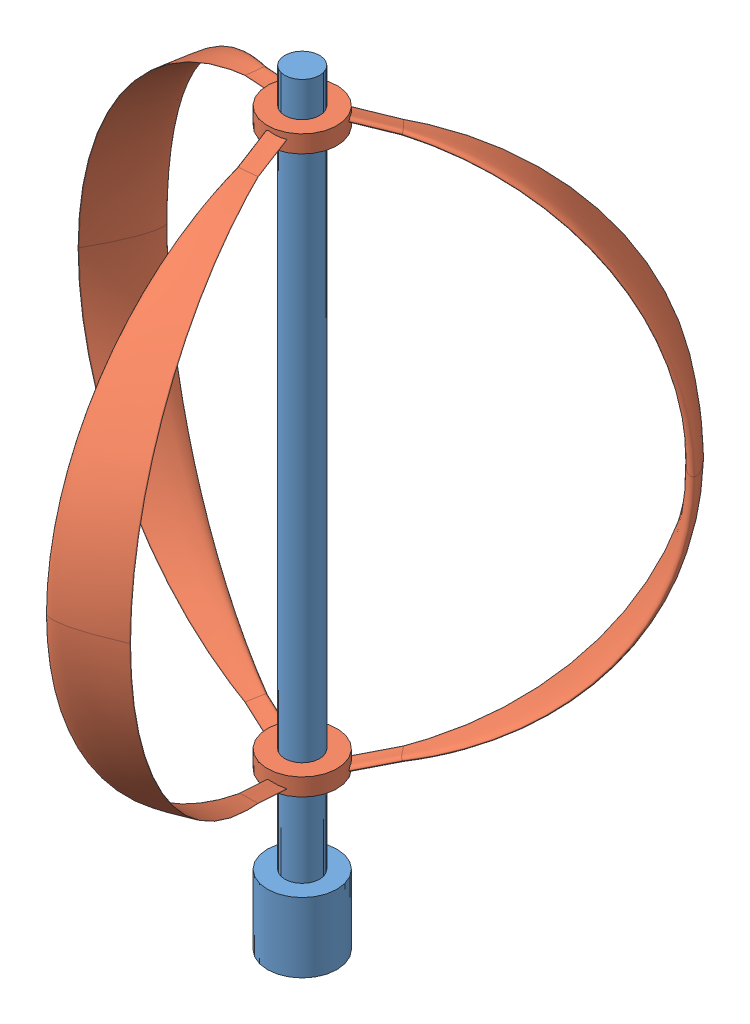
SolidWorks assembly VAWT 3-blade 3D, configuration Default. Lengths in mm.
Overall size (867.08 1100 796.54).
2 component instances, 2 part files, 2 mates.
Components (placement in the parent):
- Shaft-1: Shaft [Default] at (4.1772 11.3027 8.3636) size (100 1100 100)
- Turbine Blades-1: Turbine Blades [Default] at (39.2655 -451.1973 410.0036) x (0.977481 0 -0.211023) z (0 -1 0) size (745.9 653.86 825)
Mates (geometry in assembly coordinates):
- Concentric1: concentric: cylinder of Shaft-1 through (4.1772 -988.6973 8.3636) axis (0 1 0) radius 25; cylinder of Turbine Blades-1 through (4.1772 -14.1973 8.3636) axis (0 1 0) radius 25
- Distance1: distance = 50 mm aligned: plane of Shaft-1 through (4.1772 11.3027 8.3636) normal (0 1 0); plane of Turbine Blades-1 through (4.1772 -38.6973 8.3636) normal (0 1 0)
